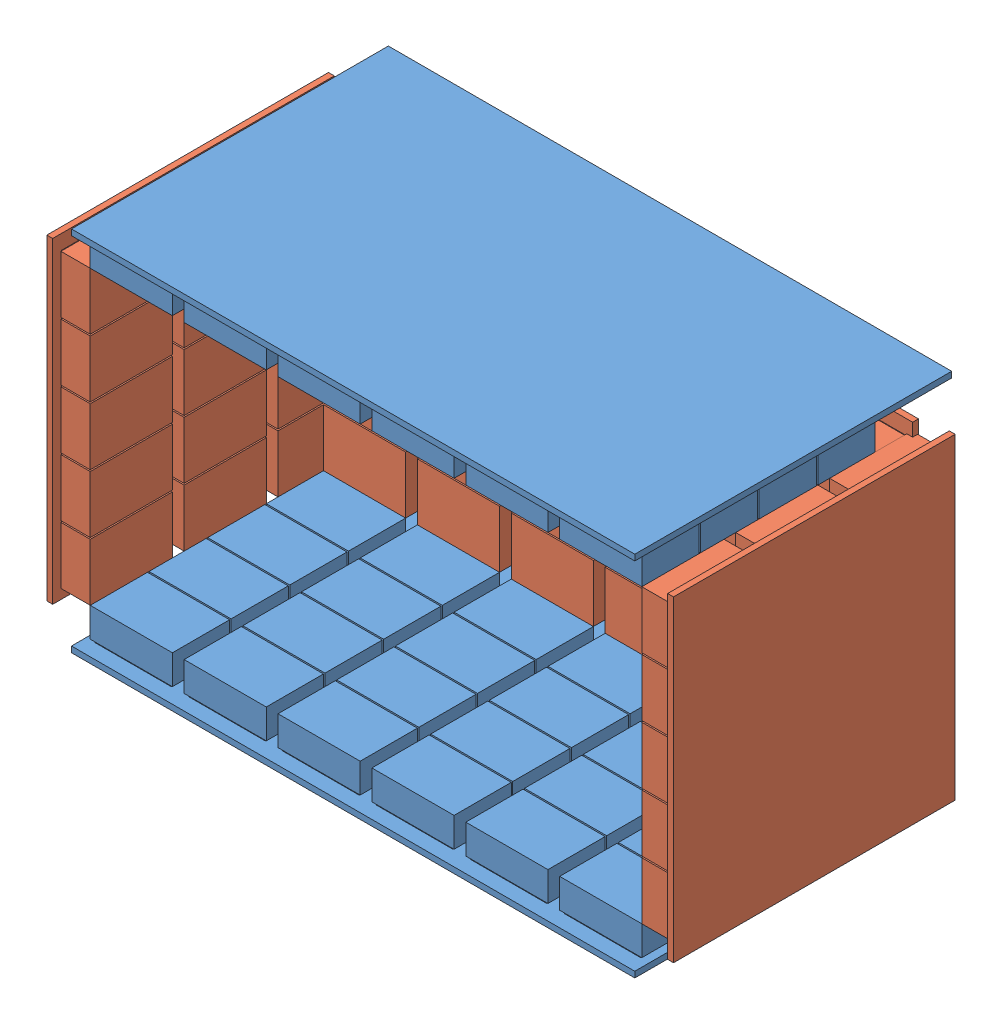
SolidWorks assembly Assembox, configuration Default. Lengths in mm.
Overall size (534 312.75 270).
6 component instances, 2 part files, 15 mates.
Components (placement in the parent):
- TopBottomDetector-1: TopBottomDetector [Default] at (341.1294 215.0718 401.7077) size (480 32 270)
- SideDetector-2: SideDetector [Default] at (408.1294 371.8113 330.7172) x (0 0 -1) z (0 1 0) size (240 32 270)
- SideDetector-3: SideDetector [Default] at (-125.8706 371.8113 490.7172) x (0 0 1) z (0 1 0) size (240 32 270)
- TopBottomDetector-2: TopBottomDetector [Default] at (-58.8706 527.8208 401.7077) x (-1 0 0) z (0 0 1) size (480 32 270)
- SideDetector-4: SideDetector [Default] at (-58.8706 371.8113 294.9683) x (-1 0 0) z (0 1 0) size (240 32 270)
- SideDetector-5: SideDetector [Default] at (181.1294 371.8113 294.9683) x (-1 0 0) z (0 1 0) size (240 32 270)
Mates (geometry in assembly coordinates):
- Coincident1: coincident anti-aligned: line of TopBottomDetector-1 through (376.1294 247.0718 525.7172) axis (0 0 -1); line of SideDetector-2 through (376.1294 247.0718 455.7172) axis (0 0 1)
- Perpendicular1: perpendicular: line of TopBottomDetector-1 through (306.1294 247.0718 525.7172) axis (1 0 0); line of SideDetector-2 through (376.1294 247.0718 525.7172) axis (0 1 0)
- Coincident3: coincident: point of TopBottomDetector-1; point of SideDetector-2
- Coincident7: coincident anti-aligned: line of TopBottomDetector-1 through (-93.8706 247.0718 476.9683) axis (0 0 1); line of SideDetector-3 through (-93.8706 247.0718 525.7172) axis (0 0 -1)
- Perpendicular3: perpendicular: line of TopBottomDetector-1 through (-93.8706 247.0718 525.7172) axis (1 0 0); line of SideDetector-3 through (-93.8706 295.8208 525.7172) axis (0 -1 0)
- Coincident9: coincident: point of TopBottomDetector-1; point of SideDetector-3
- Coincident10: coincident anti-aligned: line of SideDetector-2 through (376.1294 495.8208 525.7172) axis (0 0 -1); line of TopBottomDetector-2 through (376.1294 495.8208 476.9683) axis (0 0 1)
- Coincident11: coincident anti-aligned: line of SideDetector-3 through (-93.8706 495.8208 455.7172) axis (0 0 1); line of TopBottomDetector-2 through (-93.8706 495.8208 525.7172) axis (0 0 -1)
- Coincident12: coincident: point of SideDetector-3; point of TopBottomDetector-2
- Coincident13: coincident: line of TopBottomDetector-2 through (-93.8706 495.8208 326.9683) axis (1 0 0); line of SideDetector-4 through (-23.8706 495.8208 326.9683) axis (-1 0 0)
- Coincident14: coincident: point of TopBottomDetector-2; point of SideDetector-4
- Coincident16: coincident anti-aligned: line of TopBottomDetector-1 through (56.1294 247.0718 326.9683) axis (-1 0 0); line of SideDetector-4 through (-13.8706 247.0718 326.9683) axis (1 0 0)
- Coincident17: coincident: line of TopBottomDetector-2 through (146.1294 495.8208 326.9683) axis (1 0 0); line of SideDetector-5 through (216.1294 495.8208 326.9683) axis (-1 0 0)
- Coincident18: coincident: point of TopBottomDetector-2; point of SideDetector-5
- Coincident19: coincident anti-aligned: line of TopBottomDetector-1 through (296.1294 247.0718 326.9683) axis (-1 0 0); line of SideDetector-5 through (226.1294 247.0718 326.9683) axis (1 0 0)
